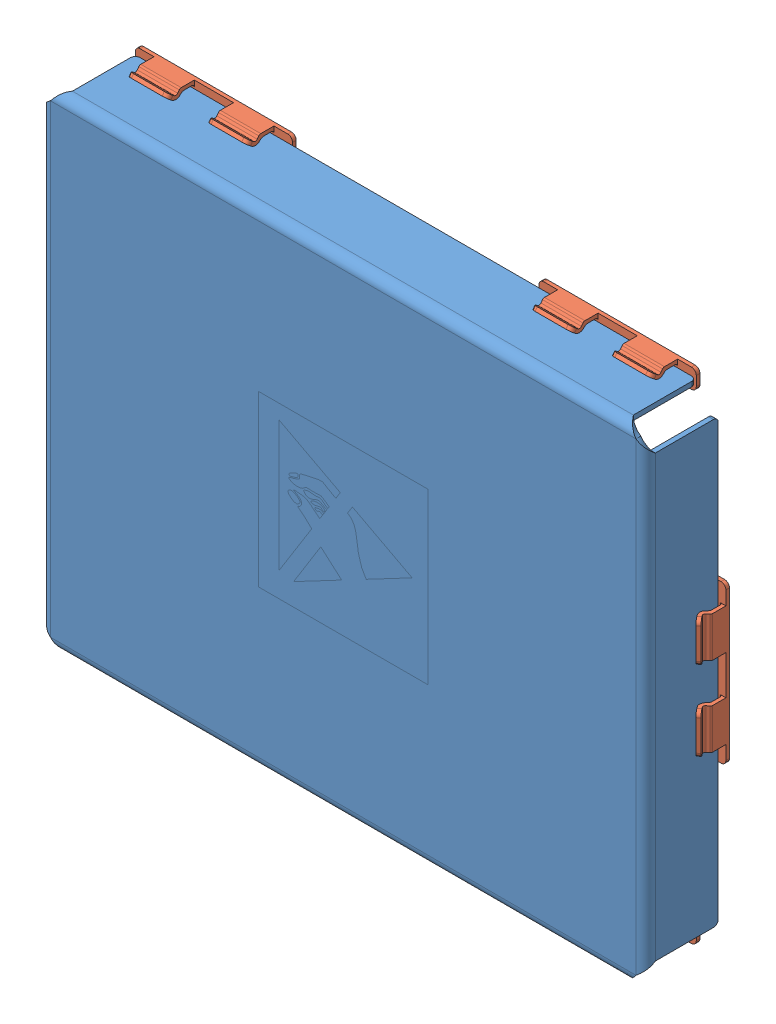
SolidWorks assembly Shield_2025_01, configuration По умолчанию. Lengths in mm.
Overall size (25.66 20.66 3.15).
7 component instances, 2 part files, 9 mates.
Components (placement in the parent):
- EMI_RFI_Shield_2025-1: EMI_RFI_Shield_2025 [По умолчанию] at origin size (25 20 3)
- EMI_RFI_MountSMD-1: EMI_RFI_MountSMD [По умолчанию] at (12.4175 0 -3.15) x (0 -1 0) z (-1 0 0) size (6.5 1.28 0.82)
- EMI_RFI_MountSMD-2: EMI_RFI_MountSMD [По умолчанию] at (8.3429 9.9175 -3.15) x (1 0 0) z (0 -1 0) size (6.5 1.28 0.82)
- EMI_RFI_MountSMD-3: EMI_RFI_MountSMD [По умолчанию] at (-8.3429 9.9175 -3.15) x (1 0 0) z (0 -1 0) size (6.5 1.28 0.82)
- EMI_RFI_MountSMD-4: EMI_RFI_MountSMD [По умолчанию] at (8.3429 -9.9175 -3.15) x (1 0 0) z (0 -1 0) size (6.5 1.28 0.82)
- EMI_RFI_MountSMD-5: EMI_RFI_MountSMD [По умолчанию] at (-8.3429 -9.9175 -3.15) x (1 0 0) z (0 -1 0) size (6.5 1.28 0.82)
- EMI_RFI_MountSMD-6: EMI_RFI_MountSMD [По умолчанию] at (-12.4175 0 -3.15) x (0 -1 0) z (-1 0 0) size (6.5 1.28 0.82)
Mates (geometry in assembly coordinates):
- Совпадение1: coincident anti-aligned: plane of EMI_RFI_Shield_2025-1 through (12.5 10 -3) normal (0 0 -1); plane of EMI_RFI_MountSMD-1 through (12.2675 -3.25 -3) normal (0 0 1)
- Касательность1: tangent anti-aligned: plane of EMI_RFI_Shield_2025-1 through (12.5 0 0) normal (1 0 0); cylinder of EMI_RFI_MountSMD-1 through (12.75 -3.25 -2.23) axis (0 1 0) radius 0.25
- Совпадение2: coincident anti-aligned: plane of EMI_RFI_MountSMD-1 through (12.4175 0 -3.15) normal (0 -1 0)
- Совпадение3: coincident anti-aligned: plane of EMI_RFI_Shield_2025-1 through (-12.5 10 -3) normal (0 0 -1); plane of EMI_RFI_MountSMD-2 through (11.5929 9.7675 -3) normal (0 0 1)
- Совпадение4: coincident aligned: plane of EMI_RFI_Shield_2025-1 through (11.5929 9.8 -0.2) normal (1 0 0); plane of EMI_RFI_MountSMD-2 through (11.5929 9.585 -2.23) normal (1 0 0)
- Касательность2: tangent anti-aligned: plane of EMI_RFI_Shield_2025-1 through (0 10 0) normal (0 1 0); cylinder of EMI_RFI_MountSMD-2 through (11.5929 10.25 -2.23) axis (-1 0 0) radius 0.25
- Совпадение5: coincident anti-aligned: plane of EMI_RFI_Shield_2025-1 through (-12.5 10 -3) normal (0 0 -1); plane of EMI_RFI_MountSMD-3 through (-5.0929 9.7675 -3) normal (0 0 1)
- Касательность3: tangent anti-aligned: plane of EMI_RFI_Shield_2025-1 through (0 10 0) normal (0 1 0); cylinder of EMI_RFI_MountSMD-3 through (-5.0929 10.25 -2.23) axis (-1 0 0) radius 0.25
- Совпадение6: coincident aligned: plane of EMI_RFI_Shield_2025-1 through (-11.5929 9.8 -0.2) normal (-1 0 0); plane of EMI_RFI_MountSMD-3 through (-11.5929 9.585 -2.23) normal (-1 0 0)
